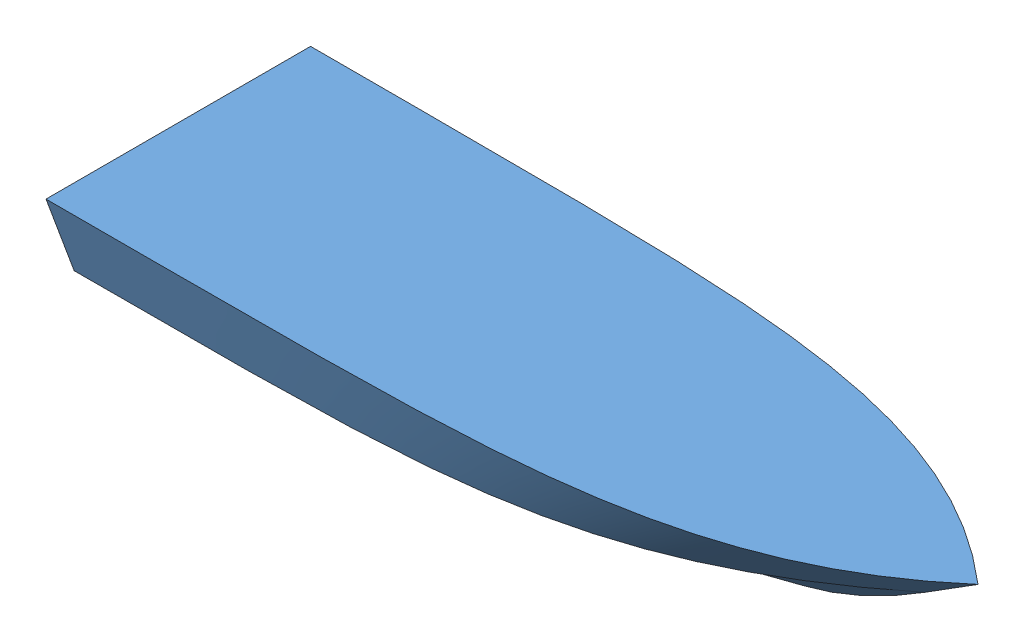
SolidWorks assembly Assem1, configuration Default. Lengths in mm.
Overall size (884.68 111.25 292.65).
2 component instances, 2 part files, 0 mates.
Components (placement in the parent):
- Hull V2-1: Hull V2 [Default] at (-3259.1505 -641.7027 700.1811) size (884.68 111.25 292.65)
- T200-THRUSTER-BLUEESC-R1-1: T200-THRUSTER-BLUEESC-R1 [Default] at (-186.691 279.1828 657.1612) x (0 0 1) z (-1 0 0) size (96.71 97.53 131.18) (hidden)
